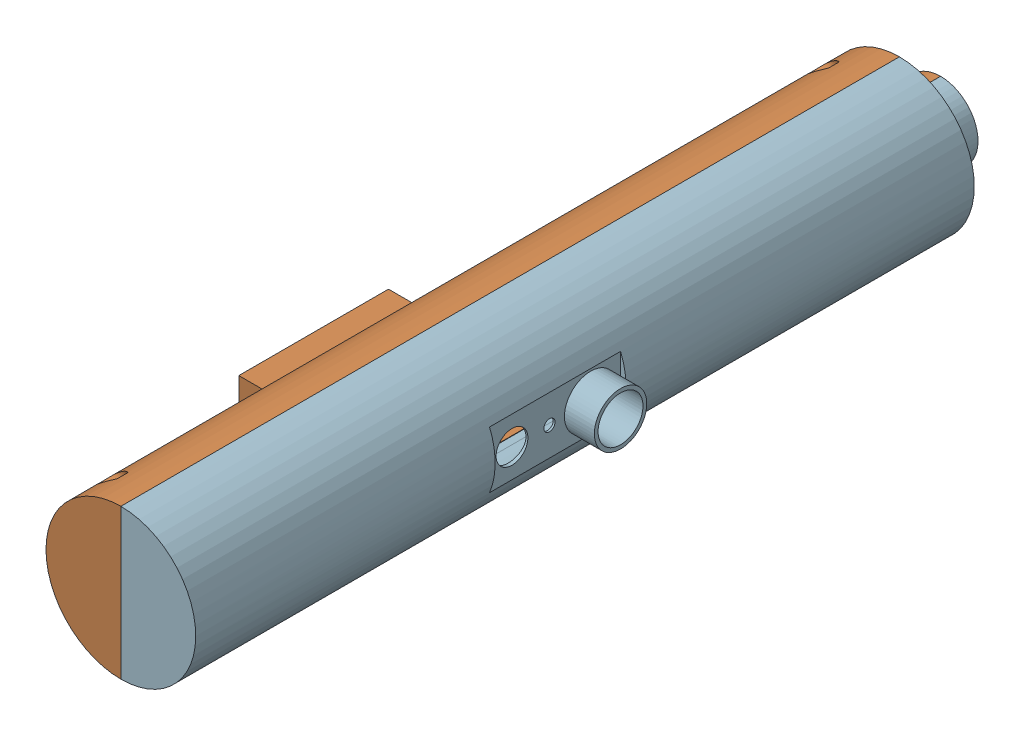
SolidWorks assembly Assembly, configuration 默认. Lengths in mm.
Overall size (54 40 219).
2 component instances, 2 part files, 3 mates.
Components (placement in the parent):
- Part A-1: Part A [默认] at (-129.9713 -28.5389 -24.7525) x (1 0 0) z (0 1 0) size (27.5 219 40)
- Part B-2: Part B [默认] at (-129.9713 -28.5389 -24.7525) x (-1 0 0) z (0 -1 0) size (28.5 219 40)
Mates (geometry in assembly coordinates):
- 重合4: coincident aligned: plane of 外壳1-1 through (-129.9713 -28.5389 190.2475) normal (0 0 1); plane of 外壳2-2 through (-129.9713 -28.5389 190.2475) normal (0 0 1)
- 重合7: coincident anti-aligned: plane of 外壳1-1 through (-131.9713 -47.5389 189.2475) normal (0 1 0); plane of 外壳2-2 through (-131.9713 -47.5389 -17.2318) normal (0 -1 0)
- 重合8: coincident anti-aligned: plane of 外壳1-1 through (-129.9713 -0.2509 197.2475) normal (1 0 0); plane of 外壳2-2 through (-129.9713 -52.263 217.2475) normal (-1 0 0)
